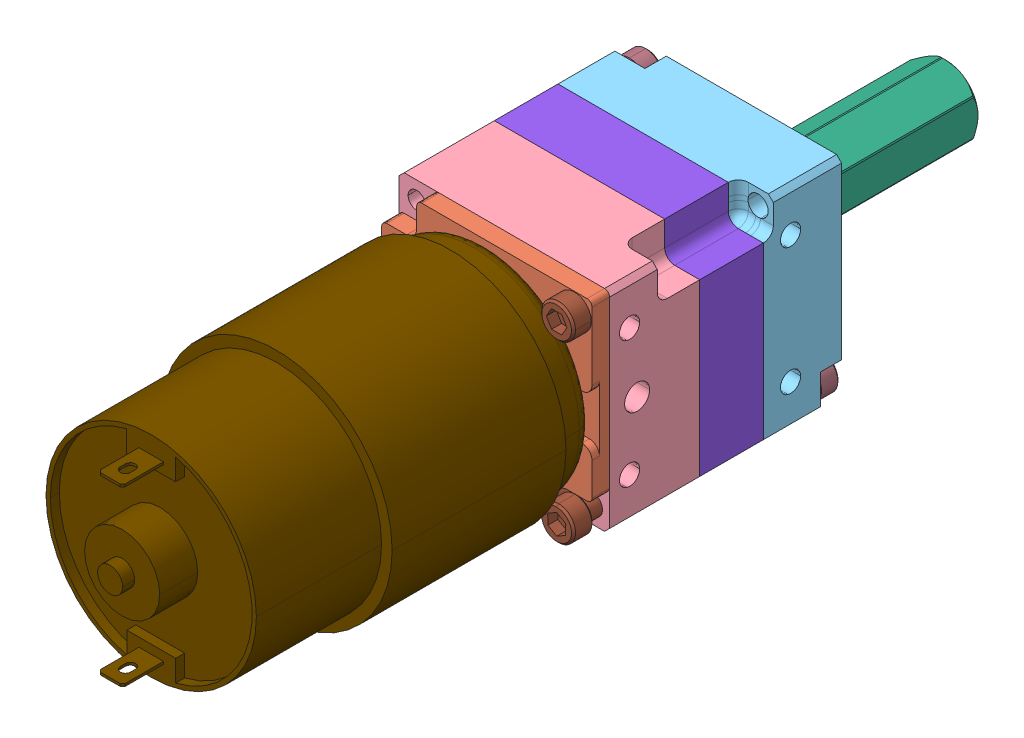
SolidWorks assembly VersaPlanetary_with_775_Pro, configuration Default. Lengths in mm.
Overall size (46.22 46.22 166.9).
32 component instances, 20 part files, 0 mates.
Components (placement in the parent):
- VersaPlanetary_v1_Single_Stage_10_1_with_775_Series.STEP-1: VersaPlanetary_v1_Single_Stage_10_1_with_775_Series.STEP [Default] at origin size (46.22 46.22 166.9)
  - 217-2625-100.STEP-1: 217-2625-100.STEP [Default] at (0 0 -18.467) x (0 1 0) z (0 0 1) size (39.22 38.88 12.7)
    - 217-2625-008 Rev1.STEP-1: 217-2625-008 Rev1.STEP [Default] at origin size (34.7 34.7 4.7)
    - 217-2625-010 Rev1.STEP-1: 217-2625-010 Rev1.STEP [Default] at (0 10.193 3.65) x (0.999813 0.019336 0) z (0 0 1) size (4 4 12)
    - 217-2625-010 Rev1.STEP-2: 217-2625-010 Rev1.STEP [Default] at (8.691 -5.3258 3.65) size (4 4 12)
    - 217-2625-010 Rev1.STEP-3: 217-2625-010 Rev1.STEP [Default] at (-8.691 -5.3258 3.65) size (4 4 12)
    - 217-2625-005 Rev1_Planet_Revolving_Follower01.STEP-1: 217-2625-005 Rev1_Planet_Revolving_Follower01.STEP [Default] at (8.691 -5.3258 6.35) x (0.932816 0.360354 0) z (0 0 1) size (16.89 16.89 8)
    - 217-2625-005 Rev1_Planet_Revolving_Follower01.STEP-2: 217-2625-005 Rev1_Planet_Revolving_Follower01.STEP [Default] at (-8.691 -5.3258 6.35) x (-0.932788 -0.360426 0) z (0 0 1) size (16.89 16.89 8)
    - 217-2625-005 Rev1_Planet_Revolving_Follower01.STEP-3: 217-2625-005 Rev1_Planet_Revolving_Follower01.STEP [Default] at (0 10.193 6.35) x (0.893583 0.448898 0) z (0 0 1) size (16.89 16.89 8)
  - 217-2625-001 Rev1.STEP-1: 217-2625-001 Rev1.STEP [Default] at origin size (42 42 18)
  - 217-2625-002 Rev1.STEP-1: 217-2625-002 Rev1.STEP [Default] at (0 0 -16.7) size (42 42 17.12)
  - 217-2625-003 Rev1.STEP-1: 217-2625-003 Rev1.STEP [Default] at (0 0 -30.9478) x (1 0 0) z (0 0 -1) size (17 17 64.11)
  - 217-2625-009 Rev1.STEP-1: 217-2625-009 Rev1.STEP [Default] at (0 0 -3.48) x (0 -1 0) z (0 0 -1) size (18 18 13)
  - 217-2816-001 Rev1.STEP-1: 217-2816-001 Rev1.STEP [Default] at (0 0 -16.85) x (1 0 0) z (0 0 -1) size (42 42 14.51)
  - 217-2625-007 Rev1_Sun_Driver01.STEP-1: 217-2625-007 Rev1_Sun_Driver01.STEP [Default] at (0 0 -11.767) x (0.055822 0.998441 0) z (0 0 1) size (15.27 15.27 12.71)
  - 217-2625-013 Rev1.STEP-1: 217-2625-013 Rev1.STEP [Default] at (0 0 1.2558) size (8 7.93 7.5)
  - SSA_SSA0832-0500ZC.STEP-1: SSA_SSA0832-0500ZC.STEP [Default] at (-17.4921 -17.5079 10.5) x (0.008716 -0.999962 0) z (-0.999962 -0.008716 0) size (6.73 16.76 6.73)
  - 217-2742.STEP-1: 217-2742.STEP [Default] at (0 0 -30.4002) x (0 0 1) z (-1 0 0) size (7 28 28)
  - 217-2742.STEP-2: 217-2742.STEP [Default] at (0 0 -38.7002) x (0 0 1) z (-0.997393 0.072165 0) size (7 28 28)
  - SSA_SSA0832-1250ZC.STEP-1: SSA_SSA0832-1250ZC.STEP [Default] at (17.5 -17.5 -34.561) x (1 0 0) z (0 1 0) size (6.73 35.81 6.73)
  - SSA_SSA0832-1250ZC.STEP-2: SSA_SSA0832-1250ZC.STEP [Default] at (-17.5 17.5 -34.561) x (1 0 0) z (0 1 0) size (6.73 35.81 6.73)
  - SSS1032-0125ZB_94105A824.STEP-1: SSS1032-0125ZB_94105A824.STEP [Default] at (-6.908 0 1.995) x (0 -0.92485 0.380331) z (-1 0 0) size (4.84 4.84 3.18)
  - 217-2625-018 Rev1_98541A410.STEP-1: 217-2625-018 Rev1_98541A410.STEP [Default] at (0 0 -22.7954) x (0 0 -1) z (0.980859 -0.194721 0) size (1 19.6 17.4)
  - 217-2625-017 Rev1_9714K61.STEP-1: 217-2625-017 Rev1_9714K61.STEP [Default] at (0 0 -31.4002) x (-0.695225 0.718792 0) z (-0.718792 -0.695225 0) size (28.51 4.98 27.43)
  - PINL-M020-006-S.STEP-1: PINL-M020-006-S.STEP [Default] at (-18.5 13.6657 -9.5) x (0 0 -1) z (1 0 0) size (6 2 2)
  - PINL-M020-006-S.STEP-2: PINL-M020-006-S.STEP [Default] at (-18.5 13.6657 -22.2) x (0 0 -1) z (0.23951 -0.970894 0) size (6 2 2)
  - BB RS775-18V.STEP-1: BB RS775-18V.STEP [Default] at (0 0 11) x (0 0 1) z (1 0.000449 0) size (88 46.2 46.2)
  - SSA_SSA0832-0500ZC.STEP-2: SSA_SSA0832-0500ZC.STEP [Default] at (17.5079 -17.4921 10.5) x (0.999962 0.008716 0) z (0.008716 -0.999962 0) size (6.73 16.76 6.73)
  - SSA_SSA0832-0500ZC.STEP-3: SSA_SSA0832-0500ZC.STEP [Default] at (17.4921 17.5079 10.5) x (-0.008716 0.999962 0) z (0.999962 0.008716 0) size (6.73 16.76 6.73)
  - SSA_SSAM4-0010ZC.STEP-1: SSA_SSAM4-0010ZC.STEP [Default] at (-0.0065 14.5 7.5) x (0.973144 0.230199 0) z (-0.230199 0.973144 0) size (7 14 7)
  - SSA_SSAM4-0010ZC.STEP-2: SSA_SSAM4-0010ZC.STEP [Default] at (0.0065 -14.5 7.5) x (0.686089 -0.727517 0) z (0.727517 0.686089 0) size (7 14 7)
  - 217-2822-002 Rev4.STEP-1: 217-2822-002 Rev4.STEP [Default] at (0 0 9.25) size (42 42 5.3)
